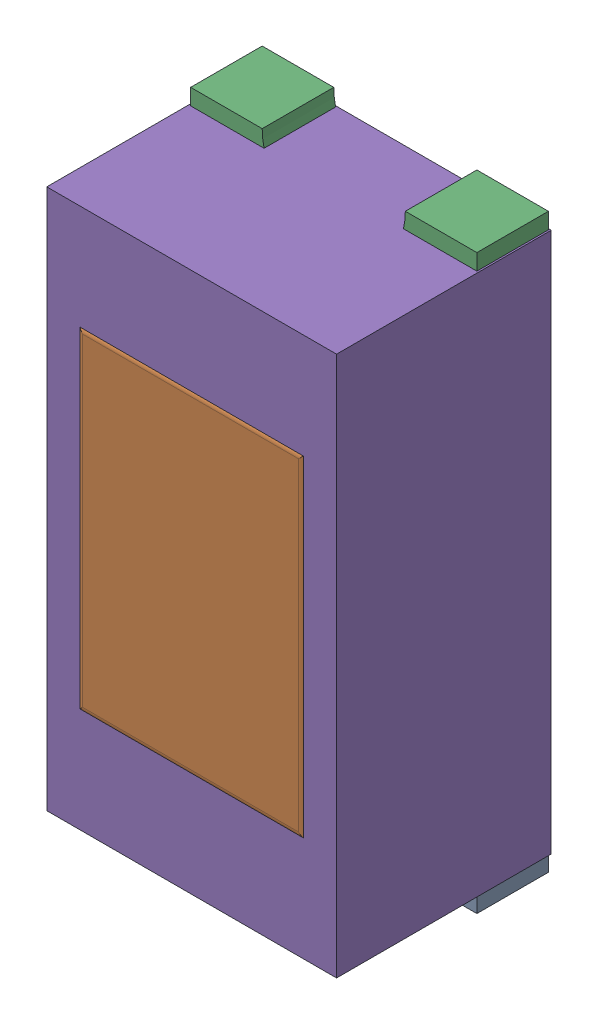
SolidWorks assembly LD4, configuration Default. Lengths in mm.
Overall size (0.81 1.61 0.61).
8 component instances, 6 part files, 0 mates.
Components (placement in the parent):
- LED_0603_GREEN-1: LED_0603_GREEN [Default] at (14.3261 2.3619 0.003) x (0 1 0) z (0 0 1) size (1.61 0.81 0.61)
  - User_Library-LED_0603_G_Pocket002-1: User_Library-LED_0603_G_Pocket002 [Default] at origin size (0.41 0.81 0.21)
  - User_Library-LED_0603_G_Pad004-1: User_Library-LED_0603_G_Pad004 [Default] x (1 0 0) z (0 0 -1) size (0.4 0.8 0)
  - User_Library-LED_0603_G_Fillet-1: User_Library-LED_0603_G_Fillet [Default] at origin size (1 0.7 0.4)
  - User_Library-LED_0603_G_Pocket001-1: User_Library-LED_0603_G_Pocket001 [Default] at origin size (0.4 0.8 0.2)
  - User_Library-LED_0603_G_Pad-1: User_Library-LED_0603_G_Pad [Default] at origin size (0.8 0.8 0.2)
- 1737248464-1: 1737248464 [Default] at (14.326 2.362 0) size (0.81 1.51 0.6)
  - Extruded-31-1: Extruded-31 [Default] at origin size (0.81 1.51 0.6)
